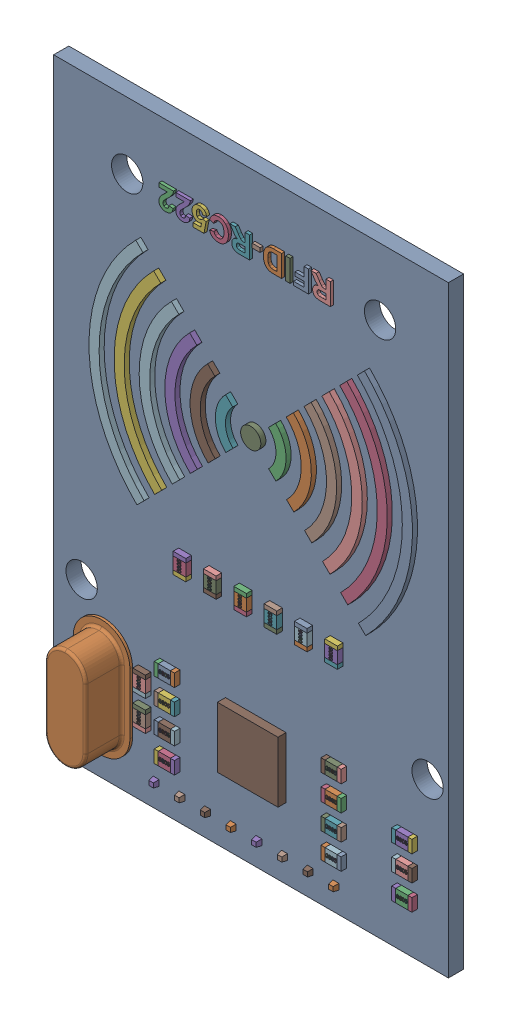
SolidWorks assembly RC522 v8.step, configuration Default. Lengths in mm.
Overall size (39.06 59.58 12.86).
35 component instances, 14 part files, 0 mates.
Components (placement in the parent):
- LED_0805_ROT v2.step-1: LED_0805_ROT v2.step [Default] at (35 2.5 1.5)
  - DCN.step-1: DCN.step [Default] at origin (suppressed, hidden)
- Komponente1.step-1: Komponente1.step [Default] at origin size (39.06 59.58 1.5)
- Komponente2.step-1: Komponente2.step [Default] at (10 0 6.8592) x (-1 0 0) z (0 0 -1) size (5.61 11.61 3.9)
- Pin Header 2,54 mm v4 (7).step-1: Pin Header 2,54 mm v4 (7).step [Default] at (10.1517 2.4012 -2.5) size (2.5 2.5 9.5)
- Pin Header 2,54 mm v4 (6).step-1: Pin Header 2,54 mm v4 (6).step [Default] at (12.6917 2.4012 -2.5) size (2.5 2.5 9.5)
- Pin Header 2,54 mm v4 (5).step-1: Pin Header 2,54 mm v4 (5).step [Default] at (15.2317 2.4012 -2.5) size (2.5 2.5 9.5)
- Pin Header 2,54 mm v4 (4).step-1: Pin Header 2,54 mm v4 (4).step [Default] at (17.7717 2.4012 -2.5) size (2.5 2.5 9.5)
- Pin Header 2,54 mm v4 (3).step-1: Pin Header 2,54 mm v4 (3).step [Default] at (20.3117 2.4012 -2.5) size (2.5 2.5 9.5)
- Pin Header 2,54 mm v4 (2).step-1: Pin Header 2,54 mm v4 (2).step [Default] at (22.8517 2.4012 -2.5) size (2.5 2.5 9.5)
- Pin Header 2,54 mm v4 (1).step-1: Pin Header 2,54 mm v4 (1).step [Default] at (25.3917 2.4012 -2.5) size (2.5 2.5 9.5)
- Pin Header 2,54 mm v4.step-1: Pin Header 2,54 mm v4.step [Default] at (27.9317 2.4012 -2.5) size (2.5 2.5 9.5)
- R-0805 v4.step-1: R-0805 v4.step [Default] at (35 5 1.5) size (2 1.25 0.57)
- R-0805 v4.step-2: R-0805 v4.step [Default] at (35 7.5 1.5) size (2 1.25 0.57)
- R-0805 v4.step-3: R-0805 v4.step [Default] at (35 10 1.5) size (2 1.25 0.57)
- R-0805 v4.step-4: R-0805 v4.step [Default] at (28 5 1.5) size (2 1.25 0.57)
- R-0805 v4.step-5: R-0805 v4.step [Default] at (28 7.5 1.5) size (2 1.25 0.57)
- R-0805 v4.step-6: R-0805 v4.step [Default] at (28 10 1.5) size (2 1.25 0.57)
- R-0805 v4.step-7: R-0805 v4.step [Default] at (28 12.5 1.5) size (2 1.25 0.57)
- R-0805 v4.step-8: R-0805 v4.step [Default] at (11.5 5 1.5) size (2 1.25 0.57)
- R-0805 v4.step-9: R-0805 v4.step [Default] at (11.5 7.5 1.5) size (2 1.25 0.57)
- R-0805 v4.step-10: R-0805 v4.step [Default] at (11.5 10 1.5) size (2 1.25 0.57)
- R-0805 v4.step-11: R-0805 v4.step [Default] at (11.5 12.5 1.5) size (2 1.25 0.57)
- R-0805 v4.step-12: R-0805 v4.step [Default] at (9 7.5 1.5) x (0 1 0) z (0 0 1) size (2 1.25 0.57)
- R-0805 v4.step-13: R-0805 v4.step [Default] at (9 10.5 1.5) x (0 1 0) z (0 0 1) size (2 1.25 0.57)
- R-0805 v4.step-14: R-0805 v4.step [Default] at (9 10.5 1.5) x (0 1 0) z (0 0 1) size (2 1.25 0.57)
- R-0805 v4.step-15: R-0805 v4.step [Default] at (28 22.5 1.5) x (0 1 0) z (0 0 1) size (2 1.25 0.57)
- R-0805 v4.step-16: R-0805 v4.step [Default] at (25 22.5 1.5) x (0 1 0) z (0 0 1) size (2 1.25 0.57)
- R-0805 v4.step-17: R-0805 v4.step [Default] at (22 22.5 1.5) x (0 1 0) z (0 0 1) size (2 1.25 0.57)
- R-0805 v4.step-18: R-0805 v4.step [Default] at (19 22.5 1.5) x (0 1 0) z (0 0 1) size (2 1.25 0.57)
- R-0805 v4.step-19: R-0805 v4.step [Default] at (16 22.5 1.5) x (0 1 0) z (0 0 1) size (2 1.25 0.57)
- R-0805 v4.step-20: R-0805 v4.step [Default] at (13 22.5 1.5) x (0 1 0) z (0 0 1) size (2 1.25 0.57)
- RC522_1.step-1: RC522_1.step [Default] at origin size (6 6 0.8)
- NFC.step-1: NFC.step [Default] at origin size (32 22.74 0.5)
- Schrift.step-1: Schrift.step [Default] at origin size (16.97 2.22 0.3)
